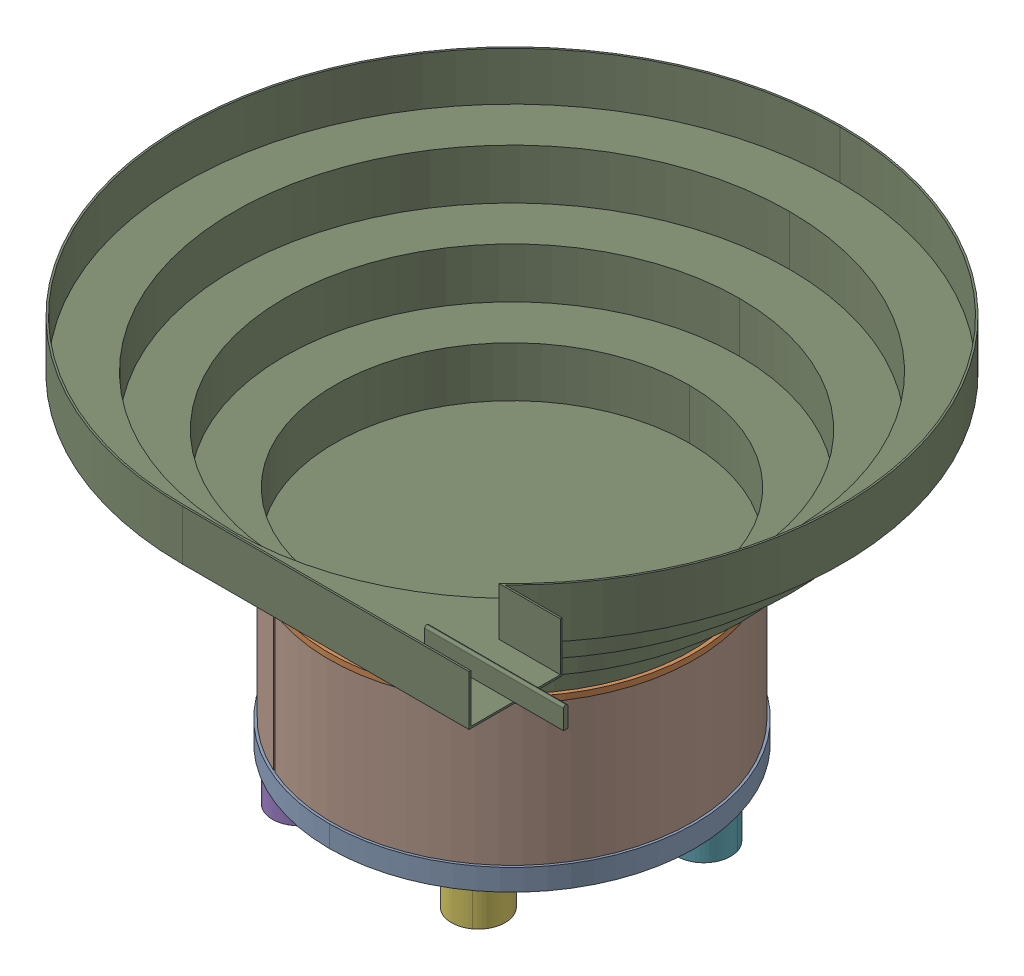
SolidWorks assembly VibratoryFeeder, configuration Default. Lengths in mm.
Overall size (930 566.38 920).
10 component instances, 5 part files, 0 mates.
Components (placement in the parent):
- IT-028-01 (DRIVE ASSEMBLY)-1: IT-028-01 (DRIVE ASSEMBLY) [Default] at origin size (705.9 286.38 705.9)
  - IT-028-01-001 (500 DRIVE BASE)-1: IT-028-01-001 (500 DRIVE BASE) [Default] at origin size (510 60 510)
  - IT-028-01-003 (500 DRIVE TOP)-1: IT-028-01-003 (500 DRIVE TOP) [Default] at (0 236.3816 0) x (-0.837169 0 -0.546944) z (-0.546944 0 0.837169) size (510 20 510)
  - M12 AV PADS-1: M12 AV PADS [Default] at (0 -50 -212.5) size (75 70 75)
  - M12 AV PADS-2: M12 AV PADS [Default] at (-202.0995 -50 -65.6661) x (0.309017 0 -0.951057) z (0.951057 0 0.309017) size (75 70 75)
  - M12 AV PADS-3: M12 AV PADS [Default] at (-124.9044 -50 171.9161) x (-0.809017 0 -0.587785) z (0.587785 0 -0.809017) size (75 70 75)
  - M12 AV PADS-4: M12 AV PADS [Default] at (124.9044 -50 171.9161) x (-0.809017 0 0.587785) z (-0.587785 0 -0.809017) size (75 70 75)
  - M12 AV PADS-5: M12 AV PADS [Default] at (202.0995 -50 -65.6661) x (0.309017 0 0.951057) z (-0.951057 0 0.309017) size (75 70 75)
  - IT-028-01-006 (COVER)-1: IT-028-01-006 (COVER) [Default] at (0 30 0) x (0.914466 0 0.404664) z (-0.404664 0 0.914466) size (503.2 198 503.19)
- 028 BOWL DEMO-1: 028 BOWL DEMO [Default] at (0 236.3816 0) size (930 280 920)
